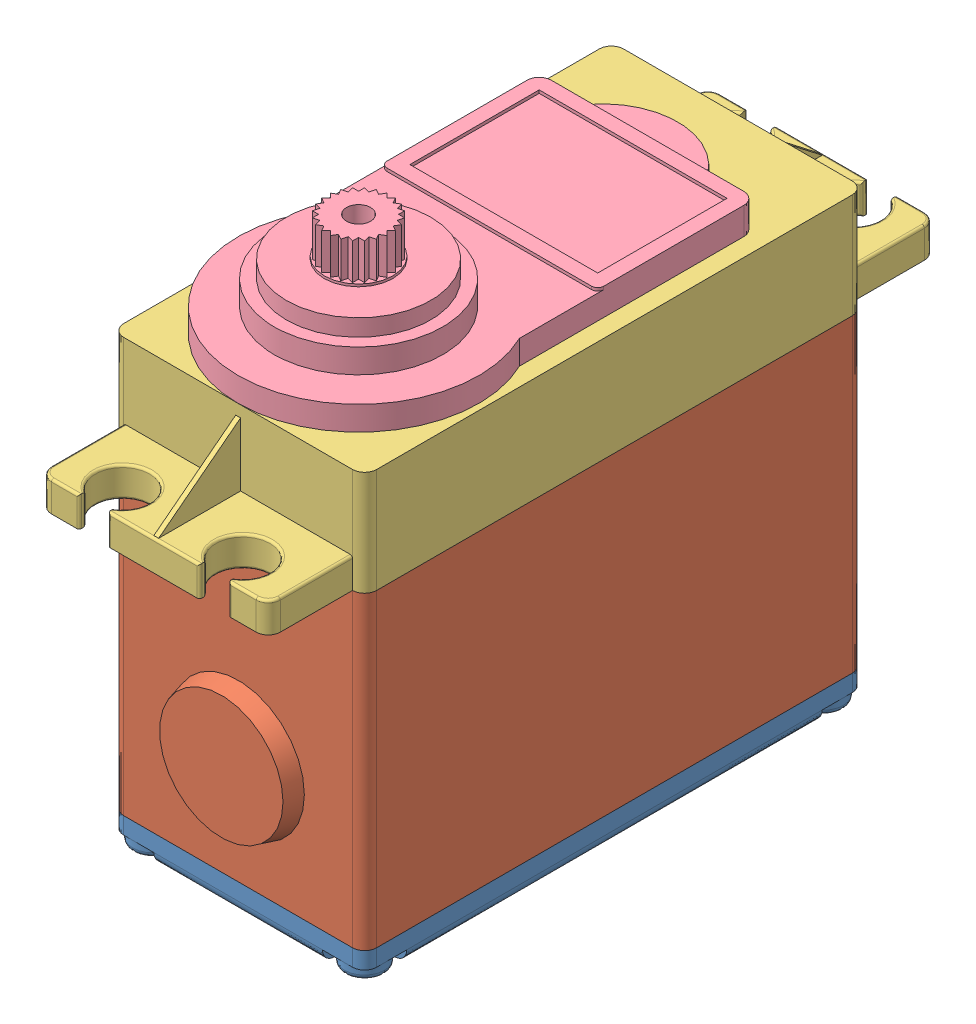
SolidWorks assembly 11886, configuration Default. Lengths in mm.
Overall size (21 45.43 55.5).
4 component instances, 4 part files, 6 mates.
Components (placement in the parent):
- 11886_bottom-1: 11886_bottom [Default] at (2.2223 -4.2785 0.9275) size (21 2.43 41.5)
- 11886_middle-1: 11886_middle [Default] at (2.2223 -1.8785 0.9275) size (21 25.7 42.9)
- 11886_upper-1: 11886_upper [Default] at (6.1473 23.8215 -5.3225) size (21 8.72 55.5)
- 11886_top-1: 11886_top [Default] at (2.2223 32.5215 0.7275) size (20 8.6 36.5)
Mates (geometry in assembly coordinates):
- Coincident1: coincident aligned: line of 11886_bottom-1 through (12.7223 -1.8785 20.6775) axis (0 0 -1); line of 11886_middle-1 through (12.7223 -1.8785 20.6775) axis (0 0 -1)
- Coincident2: coincident aligned: line of 11886_bottom-1 through (-7.2777 -1.8785 21.6775) axis (1 0 0); line of 11886_middle-1 through (-7.2777 -1.8785 21.6775) axis (1 0 0)
- Coincident3: coincident aligned: line of 11886_middle-1 through (12.7223 23.8215 20.6775) axis (0 0 -1); line of 11886_upper-1 through (12.7223 23.8215 20.6775) axis (0 0 -1)
- Concentric1: concentric aligned: cylinder of 11886_middle-1 through (11.7223 23.8215 20.6775) axis (0 -1 0) radius 1; cylinder of 11886_upper-1 through (11.7223 32.5215 20.6775) axis (0 -1 0) radius 1
- Coincident4: coincident anti-aligned: plane of 11886_upper-1 through (-8.2777 32.5215 -19.8225) normal (0 1 0); plane of 11886_top-1 through (-32.7773 32.5215 3.412) normal (0 -1 0)
- Coincident5: coincident: moEndPointRef_w of 11886_upper-1; moEndPointRef_w of 11886_top-1
